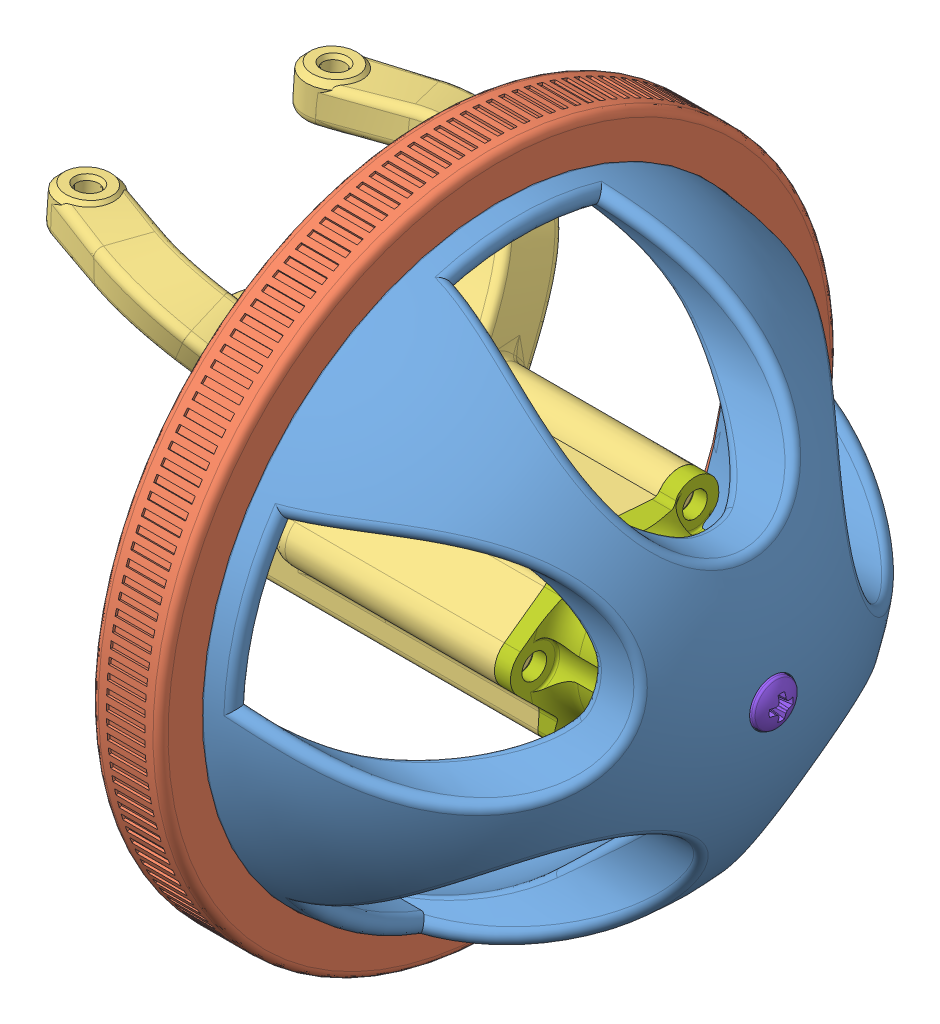
SolidWorks assembly Assem1, configuration Default. Lengths in mm.
Overall size (77.07 89.31 89.31).
9 component instances, 8 part files, 6 mates.
Components (placement in the parent):
- SD-207 EduRover Wheel00-1: SD-207 EduRover Wheel00 [Default] at (20.6037 39.1353 60.35) size (42.75 81.4 81.4)
- Pololu 90mm Tire-1: Pololu 90mm Tire [Default] at (21.3993 39.1353 60.35) x (1 0 0) z (0 0.052043 0.998645) size (8.75 85 85)
- Assem_new-1: Assem_new [Default] at (68.0654 12.8372 55.4186) x (0 0.074926 0.997189) z (-1 0 0) size (48.17 38.87 73.04)
  - SD-209 Knuckle-1: SD-209 Knuckle [Default] at (7.0379 25.8547 67.2046) size (48.17 38.87 55.78)
  - newmotor-1: newmotor [Default] at (1.8879 19.8547 40.2046) x (-1 0 0) z (0 1 0) size (10 39 12)
  - spline adapter-1: spline adapter [Default] at (6.8879 25.8547 26.9446) x (-0.997189 0.074926 0) z (-0.074926 -0.997189 0) size (9.57 19.74 9.57)
  - WW bearing-1: WW bearing [Default] at (6.8879 25.8547 18.3246) size (16 16 4.95)
  - SD-204 Wheel Bearing Retainer-1: SD-204 Wheel Bearing Retainer [Default] at (7.0379 25.8547 27.9246) x (-1 0 0) z (0 0 -1) size (25.54 24 11.1)
- 4-40 .375in BHCS McMaster 91772A108-1: 4-40 .375in BHCS McMaster 91772A108 [91772A108] at (49.8787 39.1353 60.35) x (0 -0.019737 -0.999805) z (1 0 0) size (5.56 5.56 11.83)
Mates (geometry in assembly coordinates):
- Concentric1: concentric: cylinder of SD-207 EduRover Wheel00-1 through (-979.2675 39.1353 60.35) axis (-1 0 0) radius 40.7; cylinder of Pololu 90mm Tire-1 through (-978.6007 39.1353 60.35) axis (-1 0 0) radius 40.7
- Coincident1: coincident: plane of SD-207 EduRover Wheel00-1 through (23.8537 76.3353 60.35) normal (1 0 0); plane of Pololu 90mm Tire-1 through (23.8537 78.9812 58.2735) normal (-1 0 0)
- Concentric3: concentric: cylinder of SD-207 EduRover Wheel00-1 through (-979.2675 39.1353 60.35) axis (-1 0 0) radius 1.7; circle of Assem_new-1/spline adapter-1
- Coincident4: coincident: plane of SD-207 EduRover Wheel00-1 through (57.4037 40.8353 60.35) normal (-1 0 0); plane of Assem_new-1/spline adapter-1 through (57.4037 39.1353 60.35) normal (1 0 0)
- Concentric4: concentric: cylinder of Assem_new-1/spline adapter-1 through (41.1208 39.1353 60.35) axis (-1 0 0) radius 1.295; circle of 4-40 .375in BHCS McMaster 91772A108-1
- Coincident5: coincident: plane of SD-207 EduRover Wheel00-1 through (59.4037 40.8353 60.35) normal (1 0 0); plane of 4-40 .375in BHCS McMaster 91772A108-1 through (59.4037 39.1353 60.35) normal (-1 0 0)
